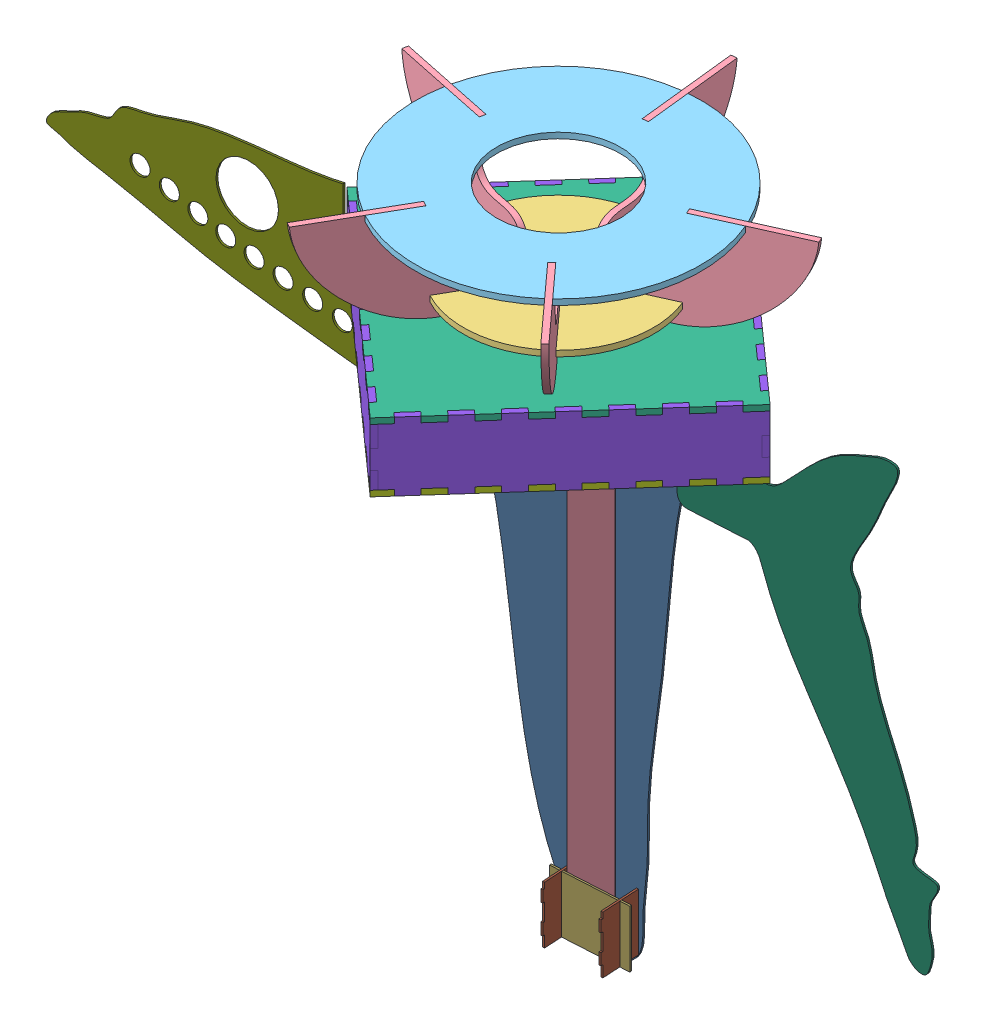
SolidWorks assembly BodyWindVoices, configuration Default. Lengths in mm.
Overall size (892.08 708.2 456.37).
29 component instances, 19 part files, 77 mates.
Components (placement in the parent):
- Axis-1: Axis [Default] at origin size (9 140 9)
- apple-1: apple [Default] at (0 70 0) x (0.686127 0 0.727482) z (0 1 0) size (45 45 80)
- topBase-2: topBase [Default] at (0 127 0) x (0.912079 0 -0.410015) z (0 -1 0) size (199.95 200 6)
- legBase-1: legBase [Default] at (-2.4862 70 1.7243) x (0.671796 0 0.740737) z (0.740737 0 -0.671796) size (162.36 115.52 6)
- legBase-2: legBase [Default] at (-2.4082 70 -1.8317) x (-0.496886 0 0.867816) z (0.867816 0 0.496886) size (162.36 115.52 6)
- legBase-3: legBase [Default] at (0.9979 70 -2.8563) x (-0.978888 0 -0.204397) z (-0.204397 0 0.978888) size (162.36 115.52 6)
- legBase-4: legBase [Default] at (3.0249 70 0.0664) x (-0.1081 0 -0.99414) z (-0.99414 0 0.1081) size (162.36 115.52 6)
- legBase-5: legBase [Default] at (0.8716 70 2.8974) x (0.912079 0 -0.410015) z (-0.410015 0 -0.912079) size (162.36 115.52 6)
- baseBase-1: baseBase [Default] at (0 209.1789 0) x (0.874011 0 0.485906) z (0 -1 0) size (300 300 6)
- baseElectComp-3: baseElectComp [Default] at (0 106 0) x (-0.74692 0 -0.664913) z (0 -1 0) size (298 298 6)
- upperElecComp-1: upperElecComp [Default] at (0 40 0) x (-0.686127 0 -0.727482) z (0 -1 0) size (322.84 322.84 6)
- side-7: side [Default] at (-99.0721 106 111.2911) x (0.74692 0 0.664913) z (-0.664913 0 0.74692) size (6 72 298)
- side-9: side [Default] at (-111.2911 106 -99.0721) x (-0.664913 0 0.74692) z (-0.74692 0 -0.664913) size (6 72 298)
- side-10: side [Default] at (99.0721 106 -111.2911) x (-0.74692 0 -0.664913) z (0.664913 0 -0.74692) size (6 72 298)
- side-12: side [Default] at (111.2911 106 99.0721) x (0.664913 0 -0.74692) z (0.74692 0 0.664913) size (6 72 298)
- Part1^BodyWindVoices-1: Part1^BodyWindVoices [Default] at (0 34 0) x (-0.686127 0 -0.727482) z (0 -1 0) (virtual)
- stepperBody-2: stepperBody [Default] at (43.2238 40 -6.0166) x (0.998317 0 -0.057988) z (0 -1 0) size (42 42 39.8)
- DorsalFin-1: DorsalFin [Default] at (0 34 0) x (-0.686127 0 -0.727482) z (0 -1 0) size (162.23 192.8 545.02)
- DorsalFin-3: DorsalFin [Default] at (2.4355 34 41.9293) x (-0.686127 0 -0.727482) z (0 -1 0) size (162.23 192.8 545.02) (hidden)
- dorsalFinTop-1: dorsalFinTop [Default] at (22.044 34 18.7533) x (0 1 0) z (-0.057988 0 -0.998317) size (60 2 44)
- dorsalFinTop-6: dorsalFinTop [Default] at (-35.8584 34 22.1166) x (0 1 0) z (-0.057988 0 -0.998317) size (60 2 44)
- Part6^BodyWindVoices-1: Part6^BodyWindVoices [Default] at (5.0726 34 19.7391) x (0 1 0) z (0.998317 0 -0.057988) (virtual)
- upperTapeHolder-1: upperTapeHolder [Default] at (5.0726 34 19.7391) x (0 1 0) z (0.998317 0 -0.057988) size (60 2 80)
- tape-1: tape [Default] at (5.0726 -416 19.7391) x (-0.998317 0 0.057988) z (0 1 0) size (48 0.1 440)
- Part9^BodyWindVoices-1: Part9^BodyWindVoices [Default] at (5.0726 24 19.7391) x (-0.998317 0 0.057988) z (0 1 0) (virtual)
- stepperShaft-1: stepperShaft [Default] at (43.2114 10 0.9709) x (0.998105 0 0.061531) z (0 1 0) size (5 5 50)
- stepperShaft-2: stepperShaft [Default] at (56.7396 45.2085 -22.5479) x (0.840962 0 -0.541094) z (0 -1 0) size (5 5 50)
- tail-2: tail [Default] at (300.2864 34 -16.4406) x (0.686127 0 0.727482) z (0 -1 0) size (169.95 202 455.5)
- head-1: head [Default] at (0 34 0) x (-0.686127 0 -0.727482) z (0 -1 0) size (264.29 314.43 163.58)
Mates (geometry in assembly coordinates):
- Concentric1: concentric anti-aligned: cylinder of Axis-1 through (0 140 0) axis (0 -1 0) radius 4.5; cylinder of apple-1 through (0 30 0) axis (0 1 0) radius 4.5
- Concentric2: concentric aligned: circle of Axis-1; cylinder of apple-1 through (0 30 0) axis (0 1 0) radius 15
- Distance1: distance = 110 mm aligned: plane of apple-1 through (0 110 0) normal (0 1 0); plane of assembly through (0 0 0) normal (0 1 0)
- Concentric4: concentric anti-aligned: circle of Axis-1; circle of topBase-2
- Distance2: distance = 11 mm anti-aligned: plane of topBase-2 through (0 121 0) normal (0 -1 0); plane of apple-1 through (0 110 0) normal (0 1 0)
- Coincident19: coincident anti-aligned: plane of topBase-2 through (51.2633 159.8869 52.0584) normal (0.671796 0 0.740737); plane of legBase-1 through (51.2633 121 52.0584) normal (-0.671796 0 -0.740737)
- Coincident20: coincident anti-aligned: plane of topBase-2 through (0 121 0) normal (0 -1 0); plane of legBase-1 through (33.1248 121 32.0585) normal (0 1 0)
- Coincident21: coincident anti-aligned: plane of topBase-2 through (46.8189 159.8869 56.0892) normal (0.740737 0 -0.671796); plane of legBase-1 through (96.5786 121.1198 110.9553) normal (-0.740737 0 0.671796)
- Coincident30: coincident aligned: plane of legBase-3 through (-204.5749 209.1789 -39.6516) normal (0 1 0); plane of baseBase-1 through (0 209.1789 0) normal (0 1 0)
- Concentric6: concentric anti-aligned: circle of topBase-2; circle of baseBase-1
- Coincident53: coincident anti-aligned: plane of apple-1 through (0 100 0) normal (0 1 0); plane of baseElectComp-3 through (0 100 0) normal (0 -1 0)
- Concentric7: concentric aligned: cylinder of apple-1 through (0 30 0) axis (0 1 0) radius 15; cylinder of baseElectComp-3 through (0 100 0) axis (0 1 0) radius 15.5
- Coincident56: coincident aligned: line of apple-1 through (0 100 0) axis (0.998317 0 -0.057988); line of baseElectComp-3 through (-210.3632 100 12.219) axis (0.998317 0 -0.057988)
- InPlace2: in place: plane of ? through (0 40 0) normal (0 -1 0); plane of ? through (0 40 0) normal (0 -1 0); moOrthogonalPlaneRef_w of ? through (0 40 0) normal (0 -1 0); plane of ? through (0 40 0) normal (0 0 -1); plane of ? through (0 40 0) normal (0 -1 0); plane of ? through (0 40 0) normal (-1 0 0); plane of apple-1 through (0 40 0) normal (0 -1 0); unknown of upperElecComp-1
- Coincident60: coincident aligned: plane of apple-1; plane of upperElecComp-1
- Coincident61: coincident aligned: moOrthogonalPlaneRef_w of apple-1; plane of upperElecComp-1 through (0 40 0) normal (0.727482 0 -0.686127)
- Coincident62: coincident anti-aligned: moOrthogonalPlaneRef_w of apple-1; plane of upperElecComp-1 through (0 40 0) normal (-0.686127 0 -0.727482)
- InPlace3: in place: plane of ? through (148.9884 100 1.8617) normal (0.999922 0 0.012495); plane of ? through (148.9884 0 1.8617) normal (0.999922 0 0.012495); plane of ? through (148.9884 100 1.8617) normal (0.999922 0 0.012495); plane of ? through (148.9884 0 1.8617) normal (0 1 0); plane of ? through (148.9884 100 1.8617) normal (0.999922 0 0.012495); plane of ? through (148.9884 0 1.8617) normal (0.012495 0 -0.999922); plane of baseElectComp-3 through (-99.0721 100 111.2911) normal (-0.664913 0 0.74692); unknown of side-7
- Coincident63: coincident aligned: plane of baseElectComp-3; plane of side-7
- Coincident64: coincident aligned: moOrthogonalPlaneRef_w of baseElectComp-3 through (-99.0721 106 111.2911) normal (0 1 0); plane of side-7 through (-99.0721 106 111.2911) normal (0 1 0)
- Coincident65: coincident anti-aligned: moOrthogonalPlaneRef_w of baseElectComp-3; plane of side-7 through (-99.0721 106 111.2911) normal (0.74692 0 0.664913)
- Coincident69: coincident aligned: plane of side-7 through (31.8312 106 -259.8464) normal (-0.74692 0 -0.664913); plane of side-9 through (-111.2911 106 -99.0721) normal (-0.74692 0 -0.664913)
- Coincident70: coincident aligned: plane of upperElecComp-1 through (0 34 0) normal (0 -1 0); plane of side-9 through (259.8464 34 31.8312) normal (0 -1 0)
- Coincident71: coincident aligned: plane of baseElectComp-3 through (99.0721 100 -111.2911) normal (0.664913 0 -0.74692); plane of side-9 through (259.8464 106 31.8312) normal (0.664913 0 -0.74692)
- Coincident74: coincident anti-aligned: plane of side-9 through (255.8569 106 36.3127) normal (-0.664913 0 0.74692); plane of side-10 through (95.0826 106 -106.8096) normal (0.664913 0 -0.74692)
- Coincident77: coincident aligned: plane of upperElecComp-1 through (0 34 0) normal (0 -1 0); plane of side-10 through (-31.8312 34 259.8464) normal (0 -1 0)
- Coincident78: coincident aligned: plane of side-9 through (111.2911 106 99.0721) normal (0.74692 0 0.664913); plane of side-10 through (-31.8312 106 259.8464) normal (0.74692 0 0.664913)
- Coincident82: coincident aligned: plane of side-10 through (-99.0721 106 111.2911) normal (-0.664913 0 0.74692); plane of side-12 through (-259.8464 106 -31.8312) normal (-0.664913 0 0.74692)
- Coincident83: coincident aligned: plane of upperElecComp-1 through (0 34 0) normal (0 -1 0); plane of side-12 through (-259.8464 34 -31.8312) normal (0 -1 0)
- Coincident84: coincident aligned: plane of side-7 through (31.8312 106 -259.8464) normal (-0.74692 0 -0.664913); plane of side-12 through (-111.2911 106 -99.0721) normal (-0.74692 0 -0.664913)
- InPlace4: in place: plane of ? through (0 34 0) normal (0 -1 0); plane of ? through (0 34 0) normal (0 -1 0); plane of ? through (0 34 0) normal (0 -1 0); plane of ? through (0 34 0) normal (0 0 -1); plane of ? through (0 34 0) normal (0 -1 0); plane of ? through (0 34 0) normal (-1 0 0); plane of upperElecComp-1 through (0 34 0) normal (0 -1 0); unknown of ?
- Coincident85: coincident aligned: plane of upperElecComp-1; plane of Part1^BodyWindVoices-1
- Coincident86: coincident aligned: moOrthogonalPlaneRef_w of upperElecComp-1; plane of Part1^BodyWindVoices-1 through (0 34 0) normal (0.727482 0 -0.686127)
- Coincident87: coincident anti-aligned: moOrthogonalPlaneRef_w of upperElecComp-1; plane of Part1^BodyWindVoices-1 through (0 34 0) normal (-0.686127 0 -0.727482)
- Perpendicular1: perpendicular: line of baseElectComp-3 through (-210.3632 100 12.219) axis (0.998317 0 -0.057988); line of stepperBody-2 through (23.4479 79.8 15.6667) axis (-0.057988 0 -0.998317)
- Distance4: distance = 0 mm: line of stepperBody-2 through (23.4479 79.8 15.6667) axis (-0.057988 0 -0.998317); cylinder of apple-1 through (0 100 0) axis (0 -1 0) radius 22.5
- InPlace5: in place: plane of ? through (0 34 0) normal (0 -1 0); plane of ? through (0 34 0) normal (0 -1 0); plane of ? through (0 34 0) normal (0 -1 0); plane of ? through (0 34 0) normal (0 0 -1); plane of ? through (0 34 0) normal (0 -1 0); plane of ? through (0 34 0) normal (-1 0 0); plane of upperElecComp-1 through (0 34 0) normal (0 -1 0); unknown of ?
- Coincident95: coincident aligned: plane of upperElecComp-1; plane of DorsalFin-1
- Coincident96: coincident aligned: moOrthogonalPlaneRef_w of upperElecComp-1; plane of DorsalFin-1 through (0 34 0) normal (0.727482 0 -0.686127)
- Coincident97: coincident anti-aligned: moOrthogonalPlaneRef_w of upperElecComp-1; plane of DorsalFin-1 through (0 34 0) normal (-0.686127 0 -0.727482)
- Coincident98: coincident anti-aligned: plane of upperElecComp-1 through (0 34 0) normal (0 -1 0); plane of DorsalFin-3 through (2.4355 34 41.9293) normal (0 1 0)
- Distance5: distance = 40 mm anti-aligned: plane of DorsalFin-1 through (123.6299 -516 -27.2148) normal (0.057988 0 0.998317); plane of DorsalFin-3 through (125.9494 -516 12.7179) normal (-0.057988 0 -0.998317)
- Coincident101: coincident aligned: line of DorsalFin-1 through (123.5139 34 -29.2114) axis (0.057988 0 0.998317); line of DorsalFin-3 through (125.9494 34 12.7179) axis (0.057988 0 0.998317)
- Coincident105: coincident anti-aligned: plane of DorsalFin-3 through (125.9494 -516 12.7179) normal (-0.057988 0 -0.998317); plane of dorsalFinTop-1 through (22.044 34 18.7533) normal (0.057988 0 0.998317)
- Distance6: distance = 450 mm anti-aligned: plane of dorsalFinTop-1 through (55.1777 -416 -83.3732) normal (0 1 0); plane of upperElecComp-1 through (0 34 0) normal (0 -1 0)
- Distance9: distance = 281 mm aligned: plane of assembly through (343.5602 34 1.0796) normal (0.998317 0 -0.057988); plane of dorsalFinTop-1 through (57.1743 -476 -83.4892) normal (0.998317 0 -0.057988)
- Distance10: distance = 58 mm aligned: plane of dorsalFinTop-1 through (55.1777 -476 -83.3732) normal (-0.998317 0 0.057988); plane of dorsalFinTop-6 through (-2.7247 -476 -80.01) normal (-0.998317 0 0.057988)
- Coincident114: coincident anti-aligned: plane of DorsalFin-1 through (123.6299 -516 -27.2148) normal (0.057988 0 0.998317); plane of dorsalFinTop-6 through (65.7275 -516 -23.8515) normal (-0.057988 0 -0.998317)
- Coincident115: coincident aligned: plane of dorsalFinTop-1 through (55.1777 -476 -83.3732) normal (0 -1 0); plane of dorsalFinTop-6 through (-2.7247 -476 -80.01) normal (0 -1 0)
- InPlace8: in place: plane of dorsalFinTop-6 through (-0.7281 -476 -80.1259) normal (0.998317 0 -0.057988); plane of ? through (3.9128 0 -0.2273) normal (0.998317 0 -0.057988); plane of dorsalFinTop-6 through (-0.7281 -476 -80.1259) normal (0.998317 0 -0.057988); plane of ? through (3.9128 0 -0.2273) normal (0 1 0); plane of dorsalFinTop-6 through (-0.7281 -476 -80.1259) normal (0.998317 0 -0.057988); plane of ? through (3.9128 0 -0.2273) normal (-0.057988 0 -0.998317); plane of dorsalFinTop-6 through (-0.7281 -476 -80.1259) normal (0.998317 0 -0.057988); unknown of ?
- Coincident119: coincident aligned: plane of dorsalFinTop-6; plane of Part6^BodyWindVoices-1
- Coincident120: coincident aligned: moOrthogonalPlaneRef_w of dorsalFinTop-6 through (5.0726 34 19.7391) normal (0.057988 0 0.998317); plane of Part6^BodyWindVoices-1 through (5.0726 34 19.7391) normal (0.057988 0 0.998317)
- Coincident121: coincident anti-aligned: moOrthogonalPlaneRef_w of dorsalFinTop-6 through (5.0726 34 19.7391) normal (0 -1 0); plane of Part6^BodyWindVoices-1 through (5.0726 34 19.7391) normal (0 1 0)
- InPlace9: in place: plane of dorsalFinTop-6 through (-0.7281 -476 -80.1259) normal (0.998317 0 -0.057988); plane of ? through (3.9128 0 -0.2273) normal (0.998317 0 -0.057988); plane of dorsalFinTop-6 through (-0.7281 -476 -80.1259) normal (0.998317 0 -0.057988); plane of ? through (3.9128 0 -0.2273) normal (0 1 0); plane of dorsalFinTop-6 through (-0.7281 -476 -80.1259) normal (0.998317 0 -0.057988); plane of ? through (3.9128 0 -0.2273) normal (-0.057988 0 -0.998317); plane of dorsalFinTop-6 through (-0.7281 -476 -80.1259) normal (0.998317 0 -0.057988); unknown of ?
- Coincident122: coincident aligned: plane of dorsalFinTop-6; plane of upperTapeHolder-1
- Coincident123: coincident aligned: moOrthogonalPlaneRef_w of dorsalFinTop-6 through (5.0726 34 19.7391) normal (0.057988 0 0.998317); plane of upperTapeHolder-1 through (5.0726 34 19.7391) normal (0.057988 0 0.998317)
- Coincident124: coincident anti-aligned: moOrthogonalPlaneRef_w of dorsalFinTop-6 through (5.0726 34 19.7391) normal (0 -1 0); plane of upperTapeHolder-1 through (5.0726 34 19.7391) normal (0 1 0)
- InPlace10: in place: plane of ? through (141.6559 -416 -9.2298) normal (0 1 0); plane of ? through (0 -416 0) normal (0 1 0); plane of ? through (141.6559 -416 -9.2298) normal (0 1 0); plane of ? through (0 -416 0) normal (0 0 -1); plane of ? through (141.6559 -416 -9.2298) normal (0 1 0); plane of ? through (0 -416 0) normal (1 0 0); plane of ? through (141.6559 -416 -9.2298) normal (0 1 0); unknown of tape-1
- Coincident125: coincident aligned: plane of upperTapeHolder-1; plane of tape-1
- Coincident126: coincident aligned: moOrthogonalPlaneRef_w of upperTapeHolder-1 through (5.0726 -416 19.7391) normal (0.057988 0 0.998317); plane of tape-1 through (5.0726 -416 19.7391) normal (0.057988 0 0.998317)
- Coincident127: coincident anti-aligned: moOrthogonalPlaneRef_w of upperTapeHolder-1 through (5.0726 -416 19.7391) normal (0.998317 0 -0.057988); plane of tape-1 through (5.0726 -416 19.7391) normal (-0.998317 0 0.057988)
- InPlace11: in place: plane of tape-1 through (5.0726 24 19.7391) normal (0 1 0); plane of ? through (0 24 0) normal (0 1 0); plane of tape-1 through (5.0726 24 19.7391) normal (0 1 0); plane of ? through (0 24 0) normal (0 0 -1); plane of tape-1 through (5.0726 24 19.7391) normal (0 1 0); plane of ? through (0 24 0) normal (1 0 0); plane of tape-1 through (5.0726 24 19.7391) normal (0 1 0); unknown of Part9^BodyWindVoices-1
- Coincident128: coincident aligned: plane of tape-1; plane of Part9^BodyWindVoices-1
- Coincident129: coincident aligned: moOrthogonalPlaneRef_w of tape-1 through (5.0726 24 19.7391) normal (0.057988 0 0.998317); plane of Part9^BodyWindVoices-1 through (5.0726 24 19.7391) normal (0.057988 0 0.998317)
- Coincident130: coincident anti-aligned: moOrthogonalPlaneRef_w of tape-1 through (5.0726 24 19.7391) normal (0.998317 0 -0.057988); plane of Part9^BodyWindVoices-1 through (5.0726 24 19.7391) normal (-0.998317 0 0.057988)
- Coincident133: coincident anti-aligned: plane of upperElecComp-1 through (0 40 0) normal (0 1 0); plane of stepperBody-2 through (43.2238 40 -6.0166) normal (0 -1 0)
- Coincident137: coincident aligned: line of upperElecComp-1 through (210.3632 40 -12.219) axis (-0.998317 0 0.057988); line of stepperBody-2 through (64.3915 40 -3.7402) axis (-0.998317 0 0.057988)
- Concentric8: concentric anti-aligned: cylinder of stepperBody-2 through (43.4268 40 -2.5225) axis (0 1 0) radius 2.5; cylinder of stepperShaft-1 through (43.4268 50 -2.5225) axis (0 -1 0) radius 2.5
- Distance11: distance = 40 mm aligned: plane of stepperShaft-1 through (43.4268 0 -2.5225) normal (0 -1 0); plane of stepperBody-2 through (43.2238 40 -6.0166) normal (0 -1 0)
- Concentric9: concentric anti-aligned: cylinder of stepperBody-2 through (58.6334 46 -19.6046) axis (0 -1 0) radius 2; cylinder of stepperShaft-2 through (58.6334 5.2085 -19.6046) axis (0 1 0) radius 2.5
- Coincident141: coincident anti-aligned: plane of upperElecComp-1 through (0 34 0) normal (0 -1 0); plane of tail-2 through (300.2864 34 -16.4406) normal (0 1 0)
- Distance13: distance = 120 mm anti-aligned: plane of assembly through (0 0 0) normal (0.998317 0 -0.057988); plane of tail-2 through (119.9141 -26 -4.9619) normal (-0.998317 0 0.057988)
- Distance14: distance = 0 mm: line of tail-2 through (144.756 34 -8.4082) axis (0.998317 0 -0.057988); line of upperElecComp-1 through (-210.3632 34 12.219) axis (0.998317 0 -0.057988)
- InPlace13: in place: plane of upperElecComp-1 through (0 34 0) normal (0 -1 0); plane of ? through (0 34 0) normal (0 -1 0); plane of upperElecComp-1 through (0 34 0) normal (0 -1 0); plane of ? through (0 34 0) normal (0 0 -1); plane of upperElecComp-1 through (0 34 0) normal (0 -1 0); plane of ? through (0 34 0) normal (-1 0 0); plane of upperElecComp-1 through (0 34 0) normal (0 -1 0); unknown of ?
- Coincident145: coincident aligned: plane of upperElecComp-1; plane of head-1
- Coincident146: coincident aligned: moOrthogonalPlaneRef_w of upperElecComp-1 through (0 34 0) normal (0.727482 0 -0.686127); plane of head-1 through (0 34 0) normal (0.727482 0 -0.686127)
- Coincident147: coincident anti-aligned: moOrthogonalPlaneRef_w of upperElecComp-1 through (0 34 0) normal (0.686127 0 0.727482); plane of head-1 through (0 34 0) normal (-0.686127 0 -0.727482)
